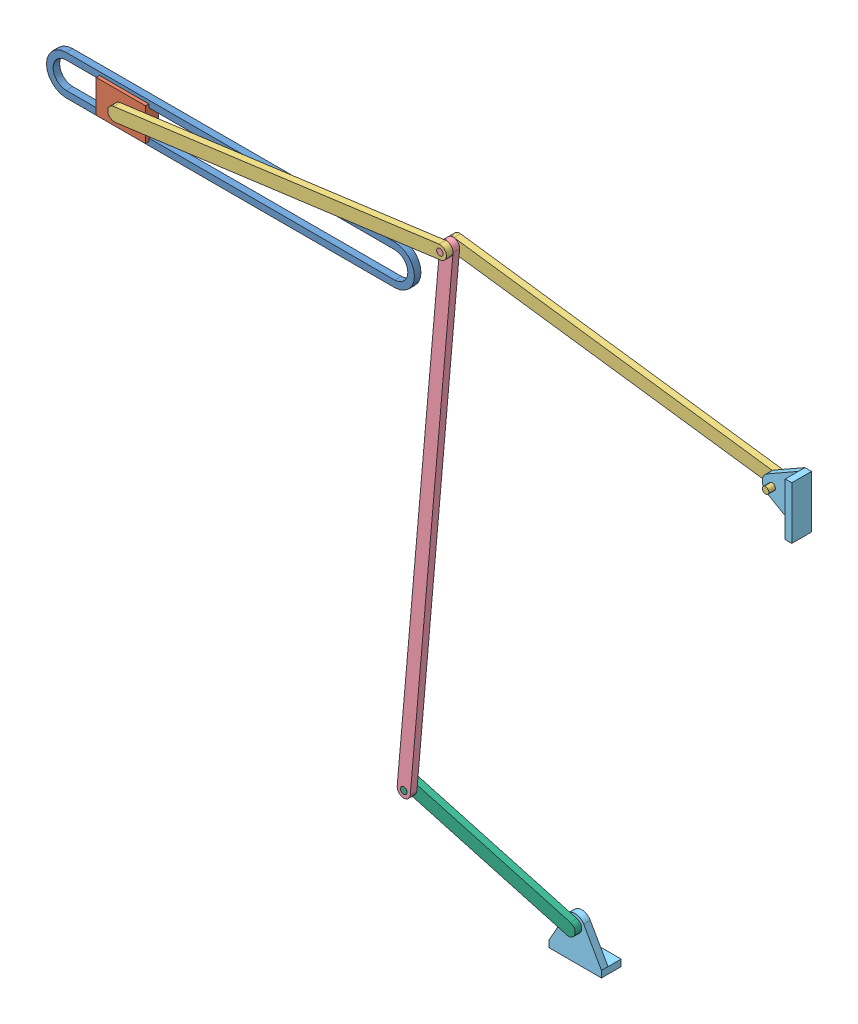
SolidWorks assembly 滑道连杆机构, configuration 默认. Lengths in mm.
Overall size (231.88 175.02 14).
8 component instances, 6 part files, 17 mates.
Components (placement in the parent):
- 滑道-1: 滑道 [默认] at (54.6777 -0.4299 0) size (112 12 2)
- 滑块-1: 滑块 [默认] at (20.0063 -0.4299 -1) size (15 10 4)
- 杆100-1: 杆100 [默认] at (60.5064 4.981 3) x (-0.991193 -0.132427 0) z (0 0 1) size (104 4 6)
- 杆150-1: 杆150 [默认] at (114.7748 -37.1574 1) x (-0.086739 -0.996231 0) z (0 0 1) size (154 4 6)
- 杆100-2: 杆100 [默认] at (177.7447 4.981 1) x (0.991193 -0.132427 0) z (0 0 -1) size (104 4 6)
- 支座-1: 支座 [默认] at (154.3032 -149.9588 -1) x (-1 0 0) z (0 0 -1) size (16 13 6)
- 支座-2: 支座 [默认] at (218.2448 -0.4299 1) x (0 1 0) z (0 0 1) size (16 13 6)
- 杆50-1: 杆50 [默认] at (138.506 -145.5867 -1) x (-0.963769 0.266738 0) z (0 0 1) size (54 4 6)
Mates (geometry in assembly coordinates):
- 重合1: coincident: plane of 滑道-1 through (2.3631 -0.4299 0) normal (0 0 -1); plane of 滑块-1 through (55.0901 4.5701 0) normal (0 0 1)
- 重合2: coincident: plane of 滑道-1 through (2.3631 3.5701 2) normal (0 -1 0); plane of 滑块-1 through (55.0901 3.5701 0) normal (0 1 0)
- 重合3: coincident: plane of 杆100-1 through (62.5901 -0.4299 -1) normal (0 0 -1); plane of 滑块-1 through (70.0901 -5.4299 -1) normal (0 0 -1)
- 同心1: concentric: cylinder of 滑块-1 through (62.5901 -0.4299 -1) axis (0 0 1) radius 1; cylinder of 杆100-1 through (62.5901 -0.4299 -1) axis (0 0 1) radius 1
- 重合4: coincident: plane of 杆100-1 through (140.4175 -63.2224 3) normal (0 0 -1); plane of 杆150-1 through (140.4175 -63.2224 3) normal (0 0 1)
- 同心2: concentric: cylinder of 杆100-1 through (140.4175 -63.2224 7) axis (0 0 -1) radius 1; cylinder of 杆150-1 through (140.4175 -63.2224 -1) axis (0 0 1) radius 1
- 重合5: coincident: plane of 杆150-1 through (140.4175 -63.2224 1) normal (0 0 -1); plane of 杆100-2 through (140.4175 -63.2224 1) normal (0 0 1)
- 同心3: concentric: cylinder of 杆150-1 through (140.4175 -63.2224 -1) axis (0 0 1) radius 1; cylinder of 杆100-2 through (140.4175 -63.2224 -3) axis (0 0 1) radius 1
- 重合6: coincident: plane of 杆100-2 through (140.4175 -63.2224 1) normal (0 0 1); plane of 支座-2 through (236.0903 -0.4299 1) normal (0 0 -1)
- 同心4: concentric: cylinder of 杆100-2 through (218.2448 -0.4299 5) axis (0 0 -1) radius 1; cylinder of 支座-2 through (218.2448 -0.4299 3) axis (0 0 -1) radius 1
- 重合9: coincident: plane of 杆150-1 through (140.4175 -63.2224 3) normal (0 0 1); plane of 杆50-1 through (129.3459 -212.8133 3) normal (0 0 1)
- 同心5: concentric: cylinder of 杆150-1 through (129.3459 -212.8133 3) axis (0 0 -1) radius 1; cylinder of 杆50-1 through (129.3459 -212.8133 3) axis (0 0 -1) radius 1
- 重合10: coincident: plane of 支座-1 through (151.0849 -185.6319 -1) normal (0 0 1); plane of 杆50-1 through (151.0849 -167.7864 -1) normal (0 0 -1)
- 同心6: concentric: cylinder of 支座-1 through (151.0849 -167.7864 -3) axis (0 0 1) radius 1; cylinder of 杆50-1 through (151.0849 -167.7864 -3) axis (0 0 1) radius 1
- 重合11: coincident: line of 滑块-1 through (54.3401 -0.4299 1) axis (1 0 0); plane of 支座-2
- 平行2: parallel aligned: plane of 滑道-1 through (2.3631 -6.4299 2) normal (0 -1 0); plane of 支座-1 through (146.3032 -159.9588 -7) normal (0 -1 0)
- 基准面1: unknown: plane of 支座-2 through (226.2448 7.5701 7) normal (0 1 0); plane of 支座-2 through (226.2448 -8.4299 7) normal (0 -1 0)
